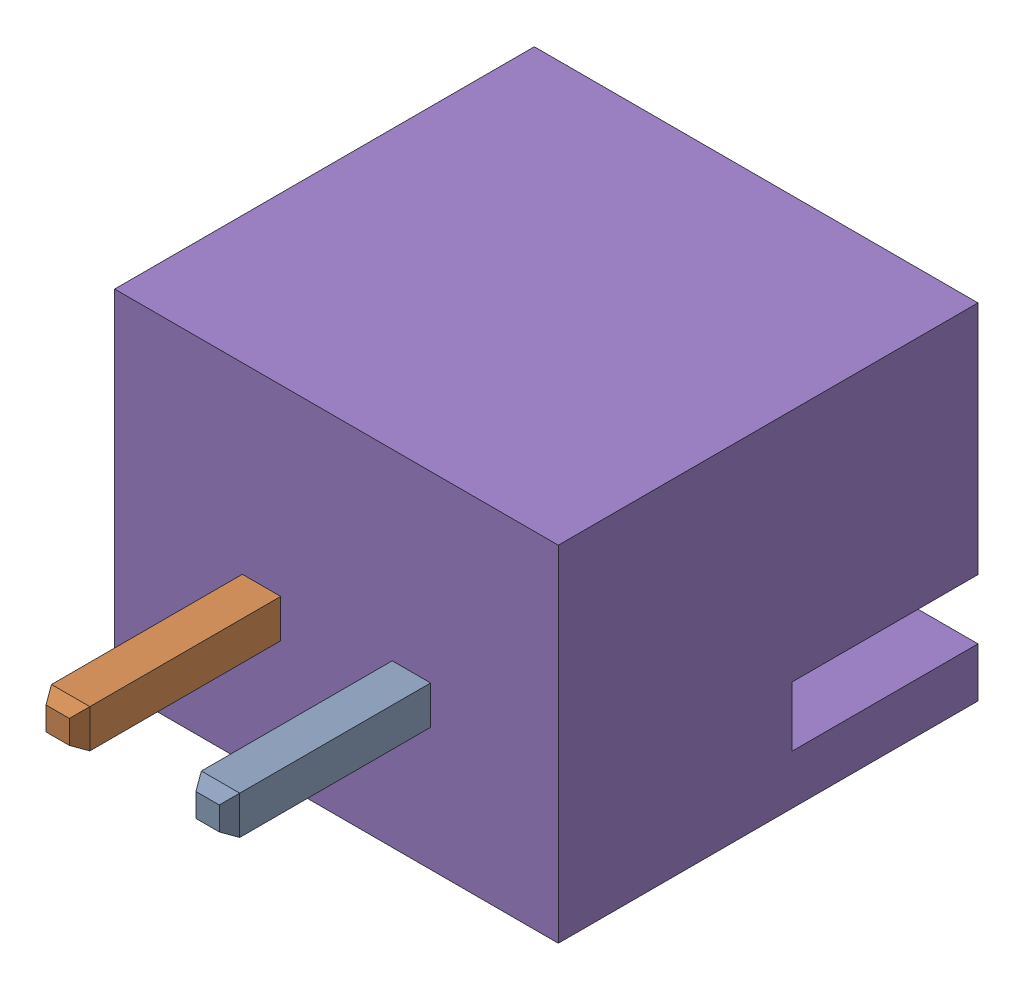
SolidWorks assembly P1, configuration Default. Lengths in mm.
Overall size (7.4 5.75 10.4).
6 component instances, 5 part files, 0 mates.
Components (placement in the parent):
- P1-subassembly-1-1: P1-subassembly-1 [Default] at (131.5051 81.6569 -0.3912) x (-1 0 0) z (0 -1 0) size (7.4 10.4 5.75)
  - User Library-JST B2B-XH-A-1: User Library-JST B2B-XH-A [Default] at origin size (0.64 3.4 0.64)
  - User Library-JST B2B-XH-A-1-1: User Library-JST B2B-XH-A-1 [Default] at origin size (0.64 3.4 0.64)
  - User Library-JST B2B-XH-A-2-1: User Library-JST B2B-XH-A-2 [Default] at origin size (0.64 4.5 0.64)
  - User Library-JST B2B-XH-A-3-1: User Library-JST B2B-XH-A-3 [Default] at origin size (0.64 4.5 0.64)
  - User Library-JST B2B-XH-A-4-1: User Library-JST B2B-XH-A-4 [Default] at origin size (7.4 7 5.75)
